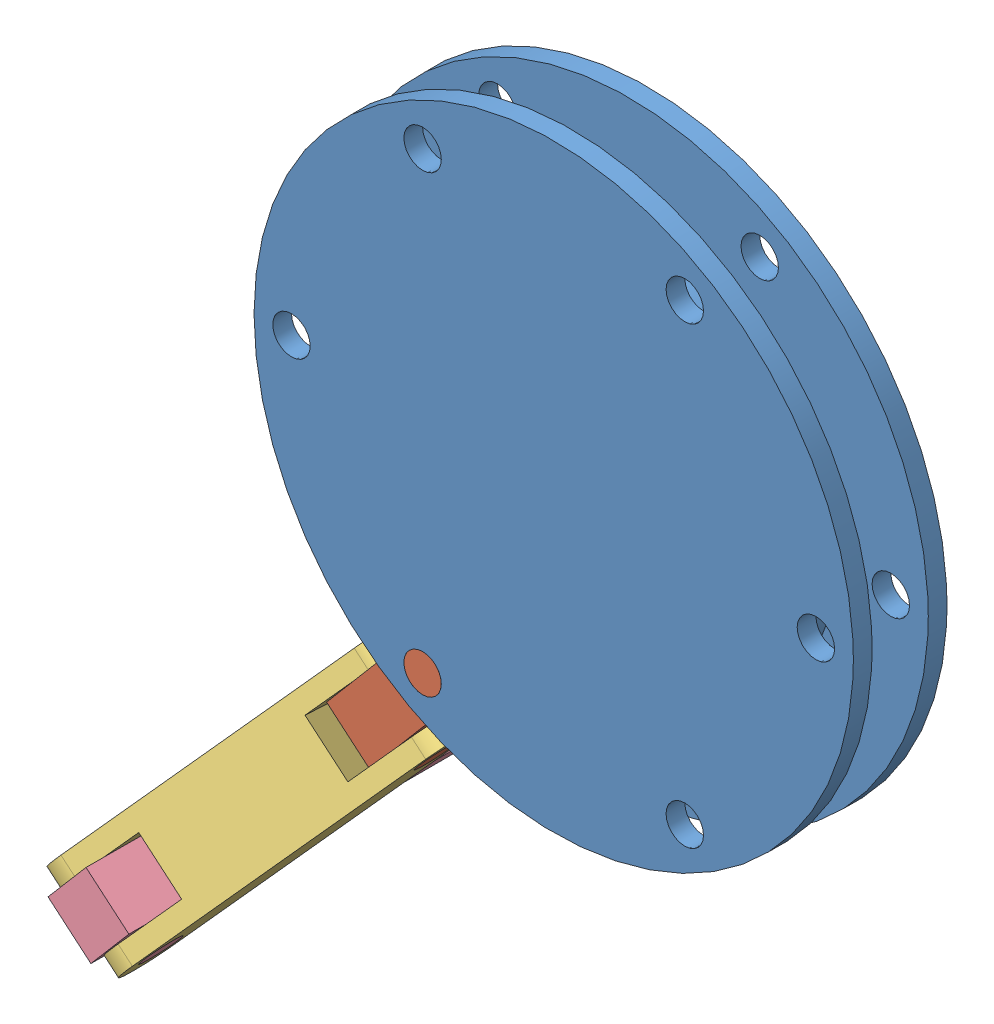
SolidWorks assembly simple_model, configuration Predeterminado. Lengths in mm.
Overall size (196.37 233.4 140.61).
4 component instances, 4 part files, 6 mates.
Components (placement in the parent):
- cama-1: cama [Predeterminado] at (9.0089 5.3707 146.8716) size (160 160 26.26)
- pata1-1: pata1 [Predeterminado] at (-25.2422 -42.7735 166.8716) x (-0.646851 -0.762616 0) z (0 0 1) size (48.5 25 25)
- pata2-2: pata2 [Predeterminado] at (-84.7269 -143.823 197.8785) x (0.601587 0.70925 -0.367502) z (-0.762616 0.646851 0) size (95.8 15 25)
- pata3-1: pata3 [Predeterminado] at (-100.408 -131.3915 197.4416) x (0.762616 -0.646851 0) z (0.01876 0.022117 0.999579) size (25 15 139.8)
Mates (geometry in assembly coordinates):
- Coincidente1: coincident: plane of assembly; plane of assembly; plane of cama-1 through (9.0089 5.3707 171.8716) normal (0 0 1); plane of pata1-1 through (-25.9911 -55.2511 171.8716) normal (0 0 1)
- Concéntrica1: concentric: circle of assembly; circle of assembly; circle of cama-1; circle of pata1-1
- Concéntrica3: concentric: circle of assembly; circle of assembly; circle of pata1-1; circle of pata2-2
- Coincidente8: coincident: plane of assembly; plane of assembly; plane of pata1-1 through (-34.8936 -85.0713 159.3716) normal (0.762616 -0.646851 0); plane of pata2-2 through (-84.7269 -143.823 197.8785) normal (0.762616 -0.646851 0)
- Concéntrica4: concentric: circle of assembly; circle of assembly; circle of pata2-2; circle of pata3-1
- Coincidente9: coincident: plane of assembly; plane of assembly; plane of pata2-2 through (-73.5003 -122.8575 188.6909) normal (-0.762616 0.646851 0); plane of pata3-1 through (-88.9687 -141.0942 197.4416) normal (0.762616 -0.646851 0)
